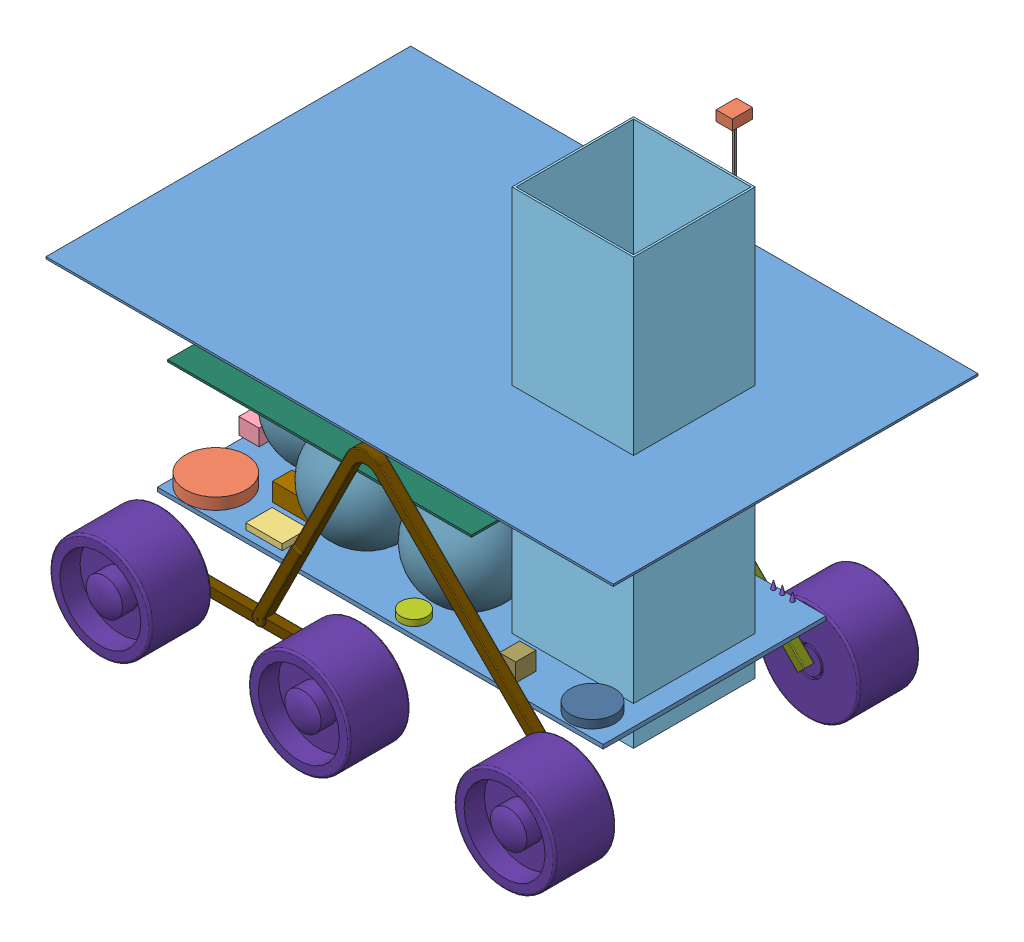
SolidWorks assembly layout_Assem_with_cover_complete_without_cover, configuration Default. Lengths in mm.
Overall size (2907.8 2551.43 1996.55).
44 component instances, 24 part files, 57 mates.
Components (placement in the parent):
- Rover_base-1: Rover_base [Default] at (-1064.6676 -0.8898 562.4151) size (2200 20 1100)
- Neutron_spectrometer-1: Neutron_spectrometer [Default] at (-926.7762 19.1102 412.2415) size (300 57 300)
- Neutron_spectrometer_electronics-1: Neutron_spectrometer_electronics [Default] at (-664.5809 19.1102 526.5713) size (180 30 130)
- gc-1: gc [Default] at (-1085.6976 19.1102 139.436) size (100 80 100)
- svr_box-1: svr_box [Default] at (435.3324 -172.8625 312.4151) size (600 2100 600)
- xrf-1: xrf [Default] at (-1008.6936 19.1102 -66.8918) size (80 90 80)
- geotechnical_exp-1: geotechnical_exp [Default] at (118.8439 19.1102 479.7148) x (0.999975 0 -0.007135) z (0.007135 0 0.999975) size (130 30 130)
- penetrometer_3-1: penetrometer_3 [Default] at (989.1282 19.1102 -518.5473) x (-0.60186 0 0.798602) z (-0.798602 0 -0.60186) size (20 40 20)
- penetrometer_3-2: penetrometer_3 [Default] at (934.1975 19.1102 -522.9905) size (20 40 20)
- penetrometer_3-3: penetrometer_3 [Default] at (890.3988 19.1102 -523.0172) x (0.957231 0 -0.289323) z (0.289323 0 0.957231) size (20 40 20)
- power-1: power [Default] at (-535.812 19.1102 343.3407) size (180 90 96)
- geotechnical_exp_vane-1: geotechnical_exp_vane [Default] at (965.2252 19.1102 444.9326) size (220 40 220)
- Magnents-1: Magnents [Default] at (-1020.4169 -10.8898 98.2252) size (45 10 45)
- Becon-1: Becon [Default] at (656.9367 19.1102 515.9957) size (80 90 100)
- Belly Cam-1: Belly Cam [Default] at (-660.0101 -90.1314 99.1462) size (150 100 150)
- power_tank-1: power_tank [Default] at (-887.862 555.3324 -63.369) x (-0.812429 0.027314 0.58242) z (0.582091 -0.01957 0.812888) size (1560.46 846.95 1367.46)
  - power_tank_10-1: power_tank_10 [Default] at (-67.1815 281.3265 414.5148) size (500 500 500)
  - power_tank_10-2: power_tank_10 [Default] at (-251.8267 476.4977 723.0274) x (0.786037 -0.315714 0.53148) z (0.083274 0.905991 0.415025) size (500 500 500)
  - power_tank_10-3: power_tank_10 [Default] at (-733.4982 325.3571 380.2859) x (0.665484 -0.133715 0.734337) z (-0.678573 0.301428 0.669836) size (500 500 500)
  - power_tank_10-4: power_tank_10 [Default] at (-1034.3616 424.6302 664.9742) x (0.724325 0.588989 -0.358392) z (-0.233278 0.698521 0.676499) size (500 500 500)
  - power_tank_10-5: power_tank_10 [Default] at (-695.3433 297.5492 1147.5051) x (0.994968 0.097333 0.023775) z (-0.042044 0.190197 0.980845) size (500 500 500)
- Tank_seperator_plate-1: Tank_seperator_plate [Default] at (435.3324 529.1102 512.4151) size (1500 10 1000)
- power_tank-3: power_tank [Default] at (-887.862 502.888 93.4377) x (-0.812429 -0.027314 -0.58242) z (0.582091 0.01957 -0.812888) size (1560.46 846.95 1367.46)
  - power_tank_10-1: power_tank_10 [Default] at (-67.1815 281.3265 414.5148) size (500 500 500)
  - power_tank_10-2: power_tank_10 [Default] at (-251.8267 476.4977 723.0274) x (0.786037 -0.315714 0.53148) z (0.083274 0.905991 0.415025) size (500 500 500)
  - power_tank_10-3: power_tank_10 [Default] at (-733.4982 325.3571 380.2859) x (0.665484 -0.133715 0.734337) z (-0.678573 0.301428 0.669836) size (500 500 500)
  - power_tank_10-4: power_tank_10 [Default] at (-1034.3616 424.6302 664.9742) x (0.724325 0.588989 -0.358392) z (-0.233278 0.698521 0.676499) size (500 500 500)
  - power_tank_10-5: power_tank_10 [Default] at (-695.3433 297.5492 1147.5051) x (0.994968 0.097333 0.023775) z (-0.042044 0.190197 0.980845) size (500 500 500)
- Rover_base_cover-1: Rover_base_cover [Default] at (1135.3324 1069.1102 -537.5849) x (1 0 0) z (0 0 -1) size (2200 1050 1100) (hidden)
- left_mobiiity_assemSLDASM-1: left_mobiiity_assemSLDASM [Default] at (483.248 -113.7012 -588.2789) x (-1 0 0) z (0 0 -1) size (2699.35 1341.14 400.39)
  - Suspension arms-1: Suspension arms [Default] at (-510.2208 -182.1885 -50.694) size (2035.36 1012.73 130)
  - wheel-1: wheel [Default] at (-515.577 -152.6706 299.306) x (-0.792605 -0.609735 0) z (0 0 -1) size (500 500 300.39)
  - wheel-2: wheel [Default] at (1479.7792 -157.1885 299.306) x (-0.72713 -0.6865 0) z (0 0 -1) size (500 500 300.39)
  - wheel-3: wheel [Default] at (499.7792 -157.1885 299.306) x (-0.949229 -0.314586 0) z (0 0 -1) size (500 500 300.39)
- right_mobiiity_assemSLDASM-1: right_mobiiity_assemSLDASM [Default] at (657.788 -311.6325 815.2315) x (-1 0 0) z (0 0 -1) size (2495.36 1237.73 400.39)
  - Suspension arms_mirror-1: Suspension arms_mirror [Default] at (-335.6808 35.7938 152.8164) size (2035.36 1012.73 130)
  - wheel-1: wheel [Default] at (1654.3192 60.7938 -97.1836) size (500 500 300.39)
  - wheel-2: wheel [Default] at (-341.0371 65.3118 -97.1836) size (500 500 300.39)
  - wheel-3: wheel [Default] at (674.3192 60.7938 -97.1836) size (500 500 300.39)
- solar cell-1: solar cell [Default] at (-1264.6676 1069.1102 -887.5849) x (-1 0 0) z (0 0 -1) size (2800 10 1800)
- stero_imaging_sys-2: stero_imaging_sys [Default] at (325.3324 1059.1102 -537.5849) size (80 548.91 402.36)
- arm-1: arm [Default] at (-1301.9354 19.1102 -517.5849) x (-1 0 0) z (0 0 -1) size (1100 100 100)
- drill-1: drill [Default] at (-665.3253 539.1102 -237.5849) size (500 200 250)
- scoop-1: scoop [Default] at (-1325.6367 25.0847 -517.5849) x (-0.755278 0.655405 0) z (0.655405 0.755278 0) size (211.36 101.82 100)
Mates (geometry in assembly coordinates):
- Coincident2: coincident anti-aligned: plane of Rover_base-1 through (-1064.6676 19.1102 -537.5849) normal (0 1 0); plane of Neutron_spectrometer-1 through (-926.7762 19.1102 412.2415) normal (0 -1 0)
- Coincident6: coincident anti-aligned: plane of Rover_base-1 through (-1064.6676 19.1102 -537.5849) normal (0 1 0); plane of Neutron_spectrometer_electronics-1 through (-664.5809 19.1102 396.5713) normal (0 -1 0)
- Coincident7: coincident anti-aligned: plane of Rover_base-1 through (-1064.6676 19.1102 -537.5849) normal (0 1 0); plane of power-1 through (-535.812 19.1102 247.3407) normal (0 -1 0)
- Coincident8: coincident anti-aligned: plane of Rover_base-1 through (-1064.6676 19.1102 -537.5849) normal (0 1 0); plane of gc-1 through (-1085.6976 19.1102 39.436) normal (0 -1 0)
- Coincident9: coincident aligned: plane of Rover_base-1 through (-1064.6676 19.1102 -537.5849) normal (0 1 0); circle of geotechnical_exp-1 centre (118.8439 19.1102 479.7148) axis (0 1 0)
- Coincident10: coincident anti-aligned: plane of Rover_base-1 through (-1064.6676 19.1102 -537.5849) normal (0 1 0); plane of xrf-1 through (-1008.6936 19.1102 -66.8918) normal (0 -1 0)
- Coincident11: coincident aligned: plane of Rover_base-1 through (-1064.6676 19.1102 -537.5849) normal (0 1 0); circle of penetrometer_3-3 centre (890.3988 19.1102 -523.0172) axis (0 1 0)
- Coincident12: coincident anti-aligned: plane of Rover_base-1 through (-1064.6676 19.1102 -537.5849) normal (0 1 0); plane of penetrometer_3-2 through (934.1975 19.1102 -522.9905) normal (0 -1 0)
- Coincident13: coincident aligned: plane of Rover_base-1 through (-1064.6676 19.1102 -537.5849) normal (0 1 0); circle of penetrometer_3-1 centre (989.1282 19.1102 -518.5473) axis (0 1 0)
- Coincident14: coincident anti-aligned: plane of Rover_base-1 through (-1064.6676 19.1102 -537.5849) normal (0 1 0); plane of geotechnical_exp_vane-1 through (965.2252 19.1102 444.9326) normal (0 -1 0)
- Coincident15: coincident anti-aligned: plane of Rover_base-1 through (-1064.6676 -0.8898 -537.5849) normal (0 -1 0); plane of Magnents-1 through (-1020.4169 -0.8898 98.2252) normal (0 1 0)
- Coincident16: coincident anti-aligned: plane of Rover_base-1 through (-1064.6676 19.1102 -537.5849) normal (0 1 0); plane of Becon-1 through (656.9367 19.1102 515.9957) normal (0 -1 0)
- Tangent1: tangent anti-aligned: plane of Rover_base-1 through (-1064.6676 19.1102 -537.5849) normal (0 1 0); sphere of power_tank-1/power_tank_10-1
- Coincident18: coincident: line of Rover_base-1; plane of svr_box-1 through (435.3324 1927.1375 312.4151) normal (-1 0 0)
- Coincident20: coincident: line of Rover_base-1; plane of svr_box-1 through (435.3324 1927.1375 -287.5849) normal (0 0 -1)
- Perpendicular2: perpendicular: line of Rover_base-1; line of svr_box-1
- Perpendicular3: perpendicular: line of Rover_base-1; line of svr_box-1
- Perpendicular4: perpendicular: line of Rover_base-1; line of svr_box-1
- Tangent12: tangent anti-aligned: plane of Rover_base-1 through (-1064.6676 19.1102 -537.5849) normal (0 1 0); sphere of power_tank-1/power_tank_10-4
- Tangent13: tangent anti-aligned: plane of Rover_base-1 through (-1064.6676 19.1102 -537.5849) normal (0 1 0); sphere of power_tank-1/power_tank_10-5
- Tangent15: tangent anti-aligned: plane of svr_box-1 through (435.3324 1927.1375 312.4151) normal (-1 0 0); sphere of power_tank-1/power_tank_10-4
- Tangent16: tangent anti-aligned: plane of svr_box-1 through (435.3324 1927.1375 312.4151) normal (-1 0 0); sphere of power_tank-1/power_tank_10-5
- Coincident25: coincident anti-aligned: plane of svr_box-1 through (435.3324 1927.1375 312.4151) normal (-1 0 0); plane of Tank_seperator_plate-1 through (435.3324 539.1102 512.4151) normal (1 0 0)
- Parallel1: parallel anti-aligned: plane of Rover_base-1 through (-1064.6676 19.1102 -537.5849) normal (0 1 0); plane of Tank_seperator_plate-1 through (435.3324 529.1102 512.4151) normal (0 -1 0)
- Distance3: distance = 200 mm: line of svr_box-1; point of Tank_seperator_plate-1
- Distance4: distance = 510 mm: plane of Rover_base-1 through (-1064.6676 19.1102 -537.5849) normal (0 1 0); line of Tank_seperator_plate-1
- Tangent29: tangent anti-aligned: plane of svr_box-1 through (435.3324 1927.1375 312.4151) normal (-1 0 0); sphere of power_tank-3/power_tank_10-5
- Tangent30: tangent anti-aligned: plane of svr_box-1 through (435.3324 1927.1375 312.4151) normal (-1 0 0); sphere of power_tank-3/power_tank_10-4
- Tangent32: tangent anti-aligned: plane of Tank_seperator_plate-1 through (435.3324 539.1102 512.4151) normal (0 1 0); sphere of power_tank-3/power_tank_10-1
- Tangent33: tangent anti-aligned: plane of Tank_seperator_plate-1 through (435.3324 539.1102 512.4151) normal (0 1 0); sphere of power_tank-3/power_tank_10-4
- Tangent34: tangent anti-aligned: plane of Tank_seperator_plate-1 through (435.3324 539.1102 512.4151) normal (0 1 0); sphere of power_tank-3/power_tank_10-5
- Coincident33: coincident anti-aligned: plane of svr_box-1 through (435.3324 1927.1375 -287.5849) normal (0 0 -1); plane of Rover_base_cover-1 through (1035.3324 669.1102 -287.5849) normal (0 0 1)
- Coincident34: coincident anti-aligned: plane of svr_box-1 through (435.3324 1927.1375 312.4151) normal (-1 0 0); plane of Rover_base_cover-1 through (435.3324 669.1102 -287.5849) normal (1 0 0)
- Coincident35: coincident anti-aligned: plane of Rover_base-1 through (-1064.6676 19.1102 -537.5849) normal (0 1 0); plane of Rover_base_cover-1 through (1135.3324 19.1102 562.4151) normal (0 -1 0)
- Coincident36: coincident anti-aligned: plane of Rover_base_cover-1 through (1135.3324 19.1102 -537.5849) normal (0 0 -1); plane of left_mobiiity_assemSLDASM-1/Suspension arms-1 through (8.4233 612.8524 -537.5849) normal (0 0 1)
- Parallel2: parallel anti-aligned: line of Rover_base-1; line of left_mobiiity_assemSLDASM-1/Suspension arms-1
- Coincident37: coincident anti-aligned: plane of Rover_base_cover-1 through (1135.3324 19.1102 562.4151) normal (0 0 1); plane of right_mobiiity_assemSLDASM-1/Suspension arms_mirror-1 through (8.4233 632.9035 562.4151) normal (0 0 -1)
- Parallel3: parallel anti-aligned: line of Rover_base_cover-1; line of right_mobiiity_assemSLDASM-1/Suspension arms_mirror-1
- Distance6: distance = 250 mm: line of Rover_base-1; line of right_mobiiity_assemSLDASM-1/Suspension arms_mirror-1
- Distance8: distance = 250 mm: line of Rover_base-1; line of left_mobiiity_assemSLDASM-1/Suspension arms-1
- Distance9: distance = 725 mm: line of Rover_base_cover-1; point of right_mobiiity_assemSLDASM-1/Suspension arms_mirror-1
- Distance10: distance = 725 mm: line of Rover_base_cover-1; point of left_mobiiity_assemSLDASM-1/Suspension arms-1
- Coincident45: coincident anti-aligned: plane of Rover_base_cover-1 through (1135.3324 1069.1102 562.4151) normal (0 1 0); plane of solar cell-1 through (-1264.6676 1069.1102 -887.5849) normal (0 -1 0)
- Coincident46: coincident anti-aligned: plane of svr_box-1 through (435.3324 1927.1375 312.4151) normal (-1 0 0); plane of solar cell-1 through (435.3324 1069.1102 -287.5849) normal (1 0 0)
- Coincident47: coincident anti-aligned: plane of svr_box-1 through (435.3324 1927.1375 312.4151) normal (0 0 1); plane of solar cell-1 through (435.3324 1069.1102 312.4151) normal (0 0 -1)
- Coincident50: coincident anti-aligned: plane of solar cell-1 through (-1264.6676 1069.1102 -887.5849) normal (0 -1 0); plane of stero_imaging_sys-2 through (335.3324 1069.1102 -884.9456) normal (0 1 0)
- Coincident51: coincident anti-aligned: plane of Rover_base_cover-1 through (1135.3324 19.1102 -537.5849) normal (0 0 -1); plane of stero_imaging_sys-2 through (335.3324 1069.1102 -537.5849) normal (0 0 1)
- Distance12: distance = 800 mm: line of Rover_base_cover-1; line of stero_imaging_sys-2
- Coincident54: coincident anti-aligned: plane of Rover_base-1 through (-1064.6676 19.1102 -537.5849) normal (0 1 0); plane of arm-1 through (-1301.9354 19.1102 -417.5849) normal (0 -1 0)
- Parallel4: parallel aligned: plane of Rover_base-1 through (-1064.6676 19.1102 -537.5849) normal (0 0 -1); plane of arm-1 through (-1301.9354 119.1102 -517.5849) normal (0 0 -1)
- Distance13: distance = 20 mm aligned: plane of Rover_base-1 through (-1064.6676 19.1102 -537.5849) normal (0 0 -1); plane of arm-1 through (-1301.9354 119.1102 -517.5849) normal (0 0 -1)
- Distance14: distance = 200 mm: plane of Rover_base-1 through (-1064.6676 19.1102 562.4151) normal (-1 0 0); point of arm-1
- Coincident58: coincident: plane of Tank_seperator_plate-1 through (435.3324 539.1102 512.4151) normal (0 1 0); plane of drill-1 through (-665.3253 539.1102 -487.5849) normal (0 -1 0)
- Coincident59: coincident: plane of Tank_seperator_plate-1 through (435.3324 539.1102 -487.5849) normal (0 0 -1); plane of drill-1 through (-665.3253 739.1102 -487.5849) normal (0 0 -1)
- Distance15: distance = 100.6577 mm aligned: plane of Tank_seperator_plate-1 through (-1064.6676 539.1102 512.4151) normal (-1 0 0); plane of drill-1 through (-1165.3253 739.1102 -237.5849) normal (-1 0 0)
- Concentric2: concentric: cylinder of arm-1; cylinder of scoop-1
- Coincident61: coincident anti-aligned: plane of arm-1 through (-1301.9354 119.1102 -467.5849) normal (0 0 1); plane of scoop-1 through (-1285.4631 22.5198 -467.5849) normal (0 0 -1)
